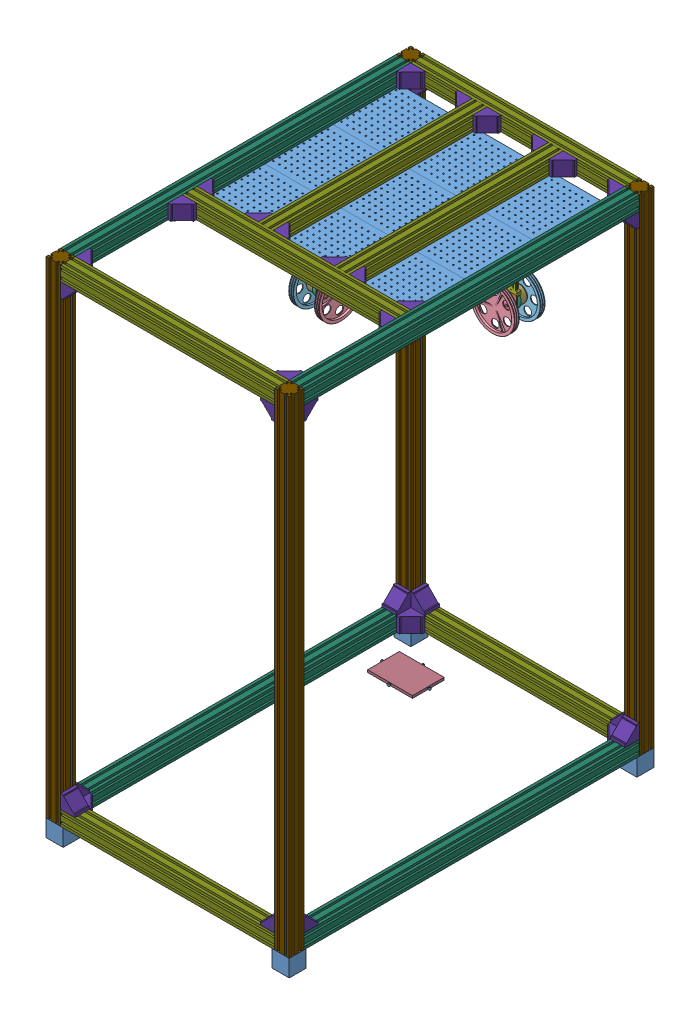
SolidWorks assembly 4轮平台（等比2：3）, configuration 默认. Lengths in mm.
Overall size (1088.36 2070 1500).
157 component instances, 22 part files, 143 mates.
Components (placement in the parent):
- 零件4^4轮平台（等比2：3）-1: 零件4^4轮平台（等比2：3） [默认] at origin (virtual)
- 零件5^4轮平台（等比2：3）-1: 零件5^4轮平台（等比2：3） [默认] at origin (virtual)
- 零件6^4轮平台（等比2：3）-1: 零件6^4轮平台（等比2：3） [默认] at origin (virtual)
- 定位板-1: 定位板 [默认] at (-160 2000 189.3477) x (-1 0 0) z (0 0 1) size (320 10 280)
- 定位板-2: 定位板 [默认] at (-480 2000 189.3477) x (-1 0 0) z (0 0 1) size (320 10 280)
- 定位板-3: 定位板 [默认] at (-800 2000 189.3477) x (-1 0 0) z (0 0 1) size (320 10 280)
- 定位板-4: 定位板 [默认] at (-800 2000 469.3477) x (-1 0 0) z (0 0 1) size (320 10 280)
- 定位板-5: 定位板 [默认] at (-480 2000 469.3477) x (-1 0 0) z (0 0 1) size (320 10 280)
- 定位板-6: 定位板 [默认] at (-160 2000 469.3477) x (-1 0 0) z (0 0 1) size (320 10 280)
- 定位板-7: 定位板 [默认] at (-160 2000 749.3477) x (-1 0 0) z (0 0 1) size (320 10 280)
- 定位板-8: 定位板 [默认] at (-480 2000 749.3477) x (-1 0 0) z (0 0 1) size (320 10 280)
- 定位板-9: 定位板 [默认] at (-800 2000 749.3477) x (-1 0 0) z (0 0 1) size (320 10 280)
- 轮装配体-6: 轮装配体 [默认] at (-1211.0387 1990 471.8477) x (-1 0 0) z (0 0 1) size (248.36 248.36 125.7)
  - 加厚加粗碳纤维竖板-6: 加厚加粗碳纤维竖板 [默认] at (-273.5387 0 0) x (-1 0 0) z (0 -1 0) size (75 5 150)
  - RoboMaster GM6020 直流无刷电机.step-1: RoboMaster GM6020 直流无刷电机.step [默认] at (-311.0387 113 -127.3479) x (0.5 0.866025 0) z (0 0 -1) size (66.7 66.7 45)
  - 卷筒2.2实验-1: 卷筒2.2实验 [默认] at (-311.0387 113 6.7) x (0.534871 -0.844933 0) z (0 0 1) size (180 180 60.8)
  - 卷筒2实验-1: 卷筒2实验 [默认] at (-311.0387 113 -44.8) x (0.534871 -0.844933 0) z (0.844933 0.534871 0) size (180 113.5 180)
  - 加厚加粗电机固定-1: 加厚加粗电机固定 [默认] at (-311.0387 113 -5) x (0.787155 -0.616755 0) z (0.616755 0.787155 0) size (73 20.3 73)
  - L型定位板-1: L型定位板 [默认] at (-361.0387 0 -5) size (100 75 47.4)
  - L型定位板-2: L型定位板 [默认] at (-261.0387 0 0) x (-1 0 0) z (0 0 -1) size (100 75 47.4)
- 轮装配体-7: 轮装配体 [默认] at (-371.0387 1990 471.8477) x (-1 0 0) z (0 0 1) size (248.36 248.36 125.7)
  - 加厚加粗碳纤维竖板-6: 加厚加粗碳纤维竖板 [默认] at (-273.5387 0 0) x (-1 0 0) z (0 -1 0) size (75 5 150)
  - RoboMaster GM6020 直流无刷电机.step-1: RoboMaster GM6020 直流无刷电机.step [默认] at (-311.0387 113 -127.3479) x (0.5 0.866025 0) z (0 0 -1) size (66.7 66.7 45)
  - 卷筒2.2实验-1: 卷筒2.2实验 [默认] at (-311.0387 113 6.7) x (0.534871 -0.844933 0) z (0 0 1) size (180 180 60.8)
  - 卷筒2实验-1: 卷筒2实验 [默认] at (-311.0387 113 -44.8) x (0.534871 -0.844933 0) z (0.844933 0.534871 0) size (180 113.5 180)
  - 加厚加粗电机固定-1: 加厚加粗电机固定 [默认] at (-311.0387 113 -5) x (0.787155 -0.616755 0) z (0.616755 0.787155 0) size (73 20.3 73)
  - L型定位板-1: L型定位板 [默认] at (-361.0387 0 -5) size (100 75 47.4)
  - L型定位板-2: L型定位板 [默认] at (-261.0387 0 0) x (-1 0 0) z (0 0 -1) size (100 75 47.4)
- 轮装配体-8: 轮装配体 [默认] at (-482.5 1990 -171.691) x (0 0 -1) z (-1 0 0) size (248.36 248.36 125.7)
  - 加厚加粗碳纤维竖板-6: 加厚加粗碳纤维竖板 [默认] at (-273.5387 0 0) x (-1 0 0) z (0 -1 0) size (75 5 150)
  - RoboMaster GM6020 直流无刷电机.step-1: RoboMaster GM6020 直流无刷电机.step [默认] at (-311.0387 113 -127.3479) x (0.5 0.866025 0) z (0 0 -1) size (66.7 66.7 45)
  - 卷筒2.2实验-1: 卷筒2.2实验 [默认] at (-311.0387 113 6.7) x (0.534871 -0.844933 0) z (0 0 1) size (180 180 60.8)
  - 卷筒2实验-1: 卷筒2实验 [默认] at (-311.0387 113 -44.8) x (0.534871 -0.844933 0) z (0.844933 0.534871 0) size (180 113.5 180)
  - 加厚加粗电机固定-1: 加厚加粗电机固定 [默认] at (-311.0387 113 -5) x (0.787155 -0.616755 0) z (0.616755 0.787155 0) size (73 20.3 73)
  - L型定位板-1: L型定位板 [默认] at (-361.0387 0 -5) size (100 75 47.4)
  - L型定位板-2: L型定位板 [默认] at (-261.0387 0 0) x (-1 0 0) z (0 0 -1) size (100 75 47.4)
- 轮装配体-9: 轮装配体 [默认] at (-477.5 1990 1110.3863) x (0 0 1) z (1 0 0) size (248.36 248.36 125.7)
  - 加厚加粗碳纤维竖板-6: 加厚加粗碳纤维竖板 [默认] at (-273.5387 0 0) x (-1 0 0) z (0 -1 0) size (75 5 150)
  - RoboMaster GM6020 直流无刷电机.step-1: RoboMaster GM6020 直流无刷电机.step [默认] at (-311.0387 113 -127.3479) x (0.5 0.866025 0) z (0 0 -1) size (66.7 66.7 45)
  - 卷筒2.2实验-1: 卷筒2.2实验 [默认] at (-311.0387 113 6.7) x (0.534871 -0.844933 0) z (0 0 1) size (180 180 60.8)
  - 卷筒2实验-1: 卷筒2实验 [默认] at (-311.0387 113 -44.8) x (0.534871 -0.844933 0) z (0.844933 0.534871 0) size (180 113.5 180)
  - 加厚加粗电机固定-1: 加厚加粗电机固定 [默认] at (-311.0387 113 -5) x (0.787155 -0.616755 0) z (0.616755 0.787155 0) size (73 20.3 73)
  - L型定位板-1: L型定位板 [默认] at (-361.0387 0 -5) size (100 75 47.4)
  - L型定位板-2: L型定位板 [默认] at (-261.0387 0 0) x (-1 0 0) z (0 0 -1) size (100 75 47.4)
- 出绳点链接板-体-1: 出绳点链接板-体 [默认] at (-439.6564 1906.0495 686.8477) x (1 0 0) z (0 0 -1) size (110.44 32.48 49)
  - 出绳点链接板-1: 出绳点链接板 [默认] at (-40.3436 16.0495 0) size (101 23 20)
  - 柱塞螺丝M6-1: 柱塞螺丝M6 [默认] at (-77.8436 22.7895 0) x (-0.70895 0 -0.705258) z (-0.705258 0 0.70895) size (12 14.74 12)
  - 柱塞螺丝M6-2: 柱塞螺丝M6 [默认] at (-2.8436 22.7895 0) x (-0.013162 0 -0.999913) z (-0.999913 0 0.013162) size (12 14.74 12)
  - 零件1^latest1-1: 零件1^latest1 [默认] at (-95.8853 -106.9505 24.5) x (0 0 -1) z (1 0 0) size (28.6 15.58 4.4)
  - 零件1^latest1-2: 零件1^latest1 [默认] at (14.5564 -106.9505 -24.5) x (0 0 1) z (-1 0 0) size (28.6 15.58 4.4)
- 出绳点链接板-体-2: 出绳点链接板-体 [默认] at (-172.5 1906.0495 509.6912) x (0 0 1) z (1 0 0) size (110.44 32.48 49)
  - 出绳点链接板-1: 出绳点链接板 [默认] at (-40.3436 16.0495 0) size (101 23 20)
  - 柱塞螺丝M6-1: 柱塞螺丝M6 [默认] at (-77.8436 22.7895 0) x (-0.70895 0 -0.705258) z (-0.705258 0 0.70895) size (12 14.74 12)
  - 柱塞螺丝M6-2: 柱塞螺丝M6 [默认] at (-2.8436 22.7895 0) x (-0.013162 0 -0.999913) z (-0.999913 0 0.013162) size (12 14.74 12)
  - 零件1^latest1-1: 零件1^latest1 [默认] at (-95.8853 -106.9505 24.5) x (0 0 -1) z (1 0 0) size (28.6 15.58 4.4)
  - 零件1^latest1-2: 零件1^latest1 [默认] at (14.5564 -106.9505 -24.5) x (0 0 1) z (-1 0 0) size (28.6 15.58 4.4)
- 出绳点链接板-体-3: 出绳点链接板-体 [默认] at (-520.3436 1906.0495 251.8477) x (-1 0 0) z (0 0 1) size (110.44 32.48 49)
  - 出绳点链接板-1: 出绳点链接板 [默认] at (-40.3436 16.0495 0) size (101 23 20)
  - 柱塞螺丝M6-1: 柱塞螺丝M6 [默认] at (-77.8436 22.7895 0) x (-0.70895 0 -0.705258) z (-0.705258 0 0.70895) size (12 14.74 12)
  - 柱塞螺丝M6-2: 柱塞螺丝M6 [默认] at (-2.8436 22.7895 0) x (-0.013162 0 -0.999913) z (-0.999913 0 0.013162) size (12 14.74 12)
  - 零件1^latest1-1: 零件1^latest1 [默认] at (-95.8853 -106.9505 24.5) x (0 0 -1) z (1 0 0) size (28.6 15.58 4.4)
  - 零件1^latest1-2: 零件1^latest1 [默认] at (14.5564 -106.9505 -24.5) x (0 0 1) z (-1 0 0) size (28.6 15.58 4.4)
- 出绳点链接板-体-4: 出绳点链接板-体 [默认] at (-787.5 1906.0495 429.0041) x (0 0 -1) z (-1 0 0) size (110.44 32.48 49)
  - 出绳点链接板-1: 出绳点链接板 [默认] at (-40.3436 16.0495 0) size (101 23 20)
  - 柱塞螺丝M6-1: 柱塞螺丝M6 [默认] at (-77.8436 22.7895 0) x (-0.70895 0 -0.705258) z (-0.705258 0 0.70895) size (12 14.74 12)
  - 柱塞螺丝M6-2: 柱塞螺丝M6 [默认] at (-2.8436 22.7895 0) x (-0.013162 0 -0.999913) z (-0.999913 0 0.013162) size (12 14.74 12)
  - 零件1^latest1-1: 零件1^latest1 [默认] at (-95.8853 -106.9505 24.5) x (0 0 -1) z (1 0 0) size (28.6 15.58 4.4)
  - 零件1^latest1-2: 零件1^latest1 [默认] at (14.5564 -106.9505 -24.5) x (0 0 1) z (-1 0 0) size (28.6 15.58 4.4)
- 单头六角柱100-16: 单头六角柱100 [默认] at (-787.5 1890 506.8477) size (18.48 108 16.01)
- 单头六角柱100-17: 单头六角柱100 [默认] at (-787.5 1890 431.8477) size (18.48 108 16.01)
- 单头六角柱100-18: 单头六角柱100 [默认] at (-172.5 1890 506.8477) size (18.48 108 16.01)
- 单头六角柱100-19: 单头六角柱100 [默认] at (-172.5 1890 431.8477) size (18.48 108 16.01)
- 单头六角柱100-20: 单头六角柱100 [默认] at (-442.5 1890 686.8477) size (18.48 108 16.01)
- 单头六角柱100-21: 单头六角柱100 [默认] at (-517.5 1890 686.8477) size (18.48 108 16.01)
- 单头六角柱100-22: 单头六角柱100 [默认] at (-517.5 1890 251.8477) size (18.48 108 16.01)
- 单头六角柱100-23: 单头六角柱100 [默认] at (-442.5 1890 251.8477) size (18.48 108 16.01)
- 定位条-9: 定位条 [默认] at (-317.7 1990 76.8477) x (-1 0 0) z (0 0 1) size (100 9.8 20.25)
- 定位条-10: 定位条 [默认] at (-317.7 1990 301.8477) x (-1 0 0) z (0 0 1) size (100 9.8 20.25)
- 定位条-11: 定位条 [默认] at (-637.7 1990 76.8477) x (-1 0 0) z (0 0 1) size (100 9.8 20.25)
- 定位条-12: 定位条 [默认] at (-637.7 1990 301.8477) x (-1 0 0) z (0 0 1) size (100 9.8 20.25)
- 定位条-13: 定位条 [默认] at (-317.7 1990 861.8477) x (-1 0 0) z (0 0 1) size (100 9.8 20.25)
- 定位条-14: 定位条 [默认] at (-317.7 1990 636.8477) x (-1 0 0) z (0 0 1) size (100 9.8 20.25)
- 定位条-15: 定位条 [默认] at (-317.7 1990 356.8477) x (-1 0 0) z (0 0 1) size (100 9.8 20.25)
- 定位条-16: 定位条 [默认] at (-317.7 1990 581.8477) x (-1 0 0) z (0 0 1) size (100 9.8 20.25)
- 定位条-17: 定位条 [默认] at (-637.7 1990 861.8477) x (-1 0 0) z (0 0 1) size (100 9.8 20.25)
- 定位条-18: 定位条 [默认] at (-637.7 1990 636.8477) x (-1 0 0) z (0 0 1) size (100 9.8 20.25)
- 定位条-19: 定位条 [默认] at (-637.7 1990 356.8477) x (-1 0 0) z (0 0 1) size (100 9.8 20.25)
- 定位条-20: 定位条 [默认] at (-637.7 1990 581.8477) x (-1 0 0) z (0 0 1) size (100 9.8 20.25)
- 定位条-21: 定位条 [默认] at (-247.5 1990 326.6477) x (0 0 -1) z (-1 0 0) size (100 9.8 20.25)
- 定位条-22: 定位条 [默认] at (-72.5 1990 326.6477) x (0 0 -1) z (-1 0 0) size (100 9.8 20.25)
- 定位条-23: 定位条 [默认] at (-247.5 1990 606.6477) x (0 0 -1) z (-1 0 0) size (100 9.8 20.25)
- 定位条-24: 定位条 [默认] at (-72.5 1990 606.6477) x (0 0 -1) z (-1 0 0) size (100 9.8 20.25)
- 定位条-25: 定位条 [默认] at (-712.5 1990 326.6477) x (0 0 -1) z (-1 0 0) size (100 9.8 20.25)
- 定位条-26: 定位条 [默认] at (-887.5 1990 326.6477) x (0 0 -1) z (-1 0 0) size (100 9.8 20.25)
- 定位条-27: 定位条 [默认] at (-712.5 1990 606.6477) x (0 0 -1) z (-1 0 0) size (100 9.8 20.25)
- 定位条-28: 定位条 [默认] at (-887.5 1990 606.6477) x (0 0 -1) z (-1 0 0) size (100 9.8 20.25)
- 铝板（2：3；130.5：184.5）-1: 铝板（2：3；130.5：184.5） [默认] at (-480 334.5585 469.3477) x (0 0 1) z (1 0 0) size (130.5 10 184.5)
- 螺丝配件-1: 螺丝配件 [默认] at (-480 329.5585 539.5977) x (0 -1 0) z (0 0 -1) size (9.5 10 18)
- 螺丝配件-2: 螺丝配件 [默认] at (-480 329.5585 399.0977) x (0 1 0) z (0 0 1) size (9.5 10 18)
- 螺丝配件-3: 螺丝配件 [默认] at (-382.75 329.5585 469.3477) x (0 -1 0) z (-1 0 0) size (9.5 10 18)
- 螺丝配件-4: 螺丝配件 [默认] at (-577.25 329.5585 469.3477) x (0 1 0) z (1 0 0) size (9.5 10 18)
- 框架-4: 框架 [默认] at (-881.2036 2030 721.2518) x (1 0 0) z (0 1 0) size (1000 1500 2070)
  - 框架（水平 大）-1: 框架（水平 大） [默认] at (-98.7964 -668.0959 30) size (60 1380 60)
  - 框架（水平 大）-2: 框架（水平 大） [默认] at (841.2036 -668.0959 30) size (60 1380 60)
  - 框架（水平 小）-1: 框架（水平 小） [默认] at (841.2036 711.9041 30) x (0 1 0) z (0 0 1) size (60 880 60)
  - 框架（水平 小）-2: 框架（水平 小） [默认] at (841.2036 -228.0959 30) x (0 1 0) z (0 0 1) size (60 880 60)
  - 框架（水平 小）-6: 框架（水平 小） [默认] at (841.2036 -728.0959 30) x (0 1 0) z (0 0 1) size (60 880 60)
  - 外角件-1: 外角件 [默认] at (-38.7964 -668.0959 -30) size (58 58 60)
  - 外角件-2: 外角件 [默认] at (841.2036 -668.0959 -30) x (0 1 0) z (0 0 1) size (58 58 60)
  - 外角件-3: 外角件 [默认] at (841.2036 -228.0959 -30) x (-1 0 0) z (0 0 1) size (58 58 60)
  - 外角件-4: 外角件 [默认] at (-38.7964 -228.0959 30) x (1 0 0) z (0 0 -1) size (58 58 60)
  - 外角件-5: 外角件 [默认] at (-38.7964 -168.0959 -30) size (58 58 60)
  - 外角件-6: 外角件 [默认] at (527.8703 -168.0959 -30) x (0 1 0) z (0 0 1) size (58 58 60)
  - 外角件-7: 外角件 [默认] at (-38.7964 711.9041 -30) x (0 -1 0) z (0 0 1) size (58 58 60)
  - 外角件-8: 外角件 [默认] at (527.8703 711.9041 30) x (0 -1 0) z (0 0 -1) size (58 58 60)
  - 外角件-9: 外角件 [默认] at (587.8703 -168.0959 -30) size (58 58 60)
  - 外角件-10: 外角件 [默认] at (841.2036 -168.0959 -30) x (0 1 0) z (0 0 1) size (58 58 60)
  - 外角件-11: 外角件 [默认] at (587.8703 711.9041 -30) x (0 -1 0) z (0 0 1) size (58 58 60)
  - 外角件-12: 外角件 [默认] at (841.2036 711.9041 -30) x (-1 0 0) z (0 0 1) size (58 58 60)
  - 框架（竖直）-1: 框架（竖直） [默认] at (-38.7964 771.9041 30) x (0 -1 0) z (1 0 0) size (60 2000 60)
  - 框架（竖直）-2: 框架（竖直） [默认] at (901.2036 711.9041 30) x (-1 0 0) z (0 -1 0) size (60 2000 60)
  - 框架（竖直）-3: 框架（竖直） [默认] at (-98.7964 -728.0959 -1970) x (1 0 0) z (0 -1 0) size (60 2000 60)
  - 框架（竖直）-4: 框架（竖直） [默认] at (841.2036 -668.0959 30) x (1 0 0) z (0 1 0) size (60 2000 60)
  - 框架（水平 小）-7: 框架（水平 小） [默认] at (841.2036 711.9041 -1970) x (0 0 1) z (0 -1 0) size (60 880 60)
  - 框架（水平 小）-8: 框架（水平 小） [默认] at (-38.7964 -668.0959 -1910) x (0 -1 0) z (0 0 1) size (60 880 60)
  - 框架（水平 大）-3: 框架（水平 大） [默认] at (901.2036 -668.0959 -1910) x (0 0 -1) z (1 0 0) size (60 1380 60)
  - 框架（水平 大）-4: 框架（水平 大） [默认] at (-98.7964 -668.0959 -1910) size (60 1380 60)
  - 外角件-13: 外角件 [默认] at (-38.7964 -668.0959 -1970) size (58 58 60)
  - 外角件-14: 外角件 [默认] at (841.2036 711.9041 -1970) x (-1 0 0) z (0 0 1) size (58 58 60)
  - 外角件-15: 外角件 [默认] at (841.2036 -668.0959 -1970) x (0 1 0) z (0 0 1) size (58 58 60)
  - 外角件-16: 外角件 [默认] at (-38.7964 711.9041 -1910) x (1 0 0) z (0 0 -1) size (58 58 60)
  - 外角件-17: 外角件 [默认] at (-98.7964 711.9041 -30) x (0 -1 0) z (1 0 0) size (58 58 60)
  - 外角件-18: 外角件 [默认] at (841.2036 -668.0959 -30) x (0 0 -1) z (1 0 0) size (58 58 60)
  - 外角件-19: 外角件 [默认] at (-38.7964 711.9041 -1910) x (0 -1 0) z (-1 0 0) size (58 58 60)
  - 外角件-20: 外角件 [默认] at (901.2036 -668.0959 -1910) x (0 0 1) z (-1 0 0) size (58 58 60)
  - 外角件-21: 外角件 [默认] at (841.2036 711.9041 -30) x (0 -1 0) z (1 0 0) size (58 58 60)
  - 外角件-22: 外角件 [默认] at (841.2036 771.9041 -1910) x (0 0 1) z (0 -1 0) size (58 58 60)
  - 外角件-23: 外角件 [默认] at (-98.7964 -668.0959 -30) x (0 0 -1) z (1 0 0) size (58 58 60)
  - 外角件-24: 外角件 [默认] at (-38.7964 -668.0959 -1910) x (0 0 1) z (-1 0 0) size (58 58 60)
  - 外角件-25: 外角件 [默认] at (841.2036 -668.0959 -1910) x (0 0 1) z (0 -1 0) size (58 58 60)
  - 外角件-26: 外角件 [默认] at (-38.7964 -728.0959 -30) x (1 0 0) z (0 1 0) size (58 58 60)
  - 外角件-27: 外角件 [默认] at (841.2036 -728.0959 -30) x (0 0 -1) z (0 1 0) size (58 58 60)
  - 外角件-28: 外角件 [默认] at (-38.7964 711.9041 -30) x (1 0 0) z (0 1 0) size (58 58 60)
  - 外角件-29: 外角件 [默认] at (-38.7964 -668.0959 -1910) x (1 0 0) z (0 -1 0) size (58 58 60)
  - 外角件-30: 外角件 [默认] at (841.2036 711.9041 -1910) x (0 0 1) z (1 0 0) size (58 58 60)
  - 外角件-31: 外角件 [默认] at (-38.7964 711.9041 -1910) x (0 0 1) z (0 1 0) size (58 58 60)
  - 外角件-32: 外角件 [默认] at (841.2036 711.9041 -30) x (0 0 -1) z (0 1 0) size (58 58 60)
  - 框架（水平 小）-9: 框架（水平 小） [默认] at (527.8703 -168.0959 30) size (60 880 60)
  - 框架（水平 小）-10: 框架（水平 小） [默认] at (214.537 -168.0959 30) size (60 880 60)
  - 外角件-33: 外角件 [默认] at (274.537 711.9041 -30) x (0 -1 0) z (0 0 1) size (58 58 60)
  - 外角件-34: 外角件 [默认] at (214.537 711.9041 -30) x (-1 0 0) z (0 0 1) size (58 58 60)
  - 外角件-35: 外角件 [默认] at (274.537 -168.0959 -30) size (58 58 60)
  - 外角件-36: 外角件 [默认] at (214.537 -168.0959 -30) x (0 1 0) z (0 0 1) size (58 58 60)
  - 支脚-1: 支脚 [默认] at (831.2036 -728.0959 -1970) size (70 70 70)
  - 支脚-2: 支脚 [默认] at (-98.7964 -728.0959 -1970) size (70 70 70)
  - 支脚-3: 支脚 [默认] at (-98.7964 701.9041 -1970) size (70 70 70)
  - 支脚-4: 支脚 [默认] at (831.2036 701.9041 -1970) size (70 70 70)
Mates (geometry in assembly coordinates):
- 平行2: parallel aligned: plane of 定位板-1 through (-160 2000 189.3477) normal (0 1 0); plane of 定位板-2 through (-480 2000 189.3477) normal (0 1 0)
- 平行6: parallel aligned: line of 定位板-1 through (-4 1990 329.3477) axis (-1 0 0); line of 定位板-2 through (-324 1990 329.3477) axis (-1 0 0)
- 重合127: coincident anti-aligned: line of 定位板-1 through (-320 2000 325.3477) axis (0 0 -1); line of 定位板-2 through (-320 2000 53.3477) axis (0 0 1)
- 重合128: coincident aligned: line of 定位板-1 through (-316 2000 49.3477) axis (1 0 0); line of 定位板-2 through (-636 2000 49.3477) axis (1 0 0)
- 重合130: coincident aligned: line of 定位板-2 through (-324 2000 329.3477) axis (-1 0 0); line of 定位板-3 through (-644 2000 329.3477) axis (-1 0 0)
- 重合132: coincident anti-aligned: line of 定位板-2 through (-640 2000 325.3477) axis (0 0 -1); line of 定位板-3 through (-640 2000 53.3477) axis (0 0 1)
- 重合193: coincident anti-aligned: plane of 定位板-3 through (-640 1990 329.3477) normal (0 0 1); plane of 定位板-4 through (-640 1990 329.3477) normal (0 0 -1)
- 重合194: coincident aligned: plane of 定位板-3 through (-800 1990 189.3477) normal (0 -1 0); plane of 定位板-4 through (-800 1990 469.3477) normal (0 -1 0)
- 重合195: coincident aligned: plane of 定位板-3 through (-960 1990 329.3477) normal (-1 0 0); plane of 定位板-4 through (-960 1990 609.3477) normal (-1 0 0)
- 重合196: coincident anti-aligned: plane of 定位板-4 through (-640 1990 609.3477) normal (1 0 0); plane of 定位板-5 through (-640 1990 609.3477) normal (-1 0 0)
- 重合197: coincident anti-aligned: plane of 定位板-2 through (-320 1990 329.3477) normal (0 0 1); plane of 定位板-5 through (-320 1990 329.3477) normal (0 0 -1)
- 重合198: coincident aligned: plane of 定位板-2 through (-480 1990 189.3477) normal (0 -1 0); plane of 定位板-5 through (-480 1990 469.3477) normal (0 -1 0)
- 重合199: coincident anti-aligned: plane of 定位板-5 through (-320 1990 609.3477) normal (1 0 0); plane of 定位板-6 through (-320 1990 609.3477) normal (-1 0 0)
- 重合200: coincident aligned: plane of 定位板-5 through (-480 1990 469.3477) normal (0 -1 0); plane of 定位板-6 through (-160 1990 469.3477) normal (0 -1 0)
- 重合201: coincident: line of 定位板-1 through (-4 1990 329.3477) axis (-1 0 0); plane of 定位板-6 through (0 1990 329.3477) normal (0 0 -1)
- 重合214: coincident aligned: line of 定位板-8 through (-324 2000 889.3477) axis (-1 0 0); line of 定位板-9 through (-644 2000 889.3477) axis (-1 0 0)
- 重合215: coincident aligned: line of 定位板-7 through (-4 2000 889.3477) axis (-1 0 0); line of 定位板-8 through (-324 2000 889.3477) axis (-1 0 0)
- 重合216: coincident anti-aligned: plane of 定位板-7 through (-320 1990 889.3477) normal (-1 0 0); plane of 定位板-8 through (-320 1990 889.3477) normal (1 0 0)
- 重合217: coincident anti-aligned: plane of 定位板-8 through (-640 1990 889.3477) normal (-1 0 0); plane of 定位板-9 through (-640 1990 889.3477) normal (1 0 0)
- 重合221: coincident anti-aligned: plane of 定位板-4 through (-800 1990 469.3477) normal (0 -1 0); plane of 轮装配体-6/L型定位板-2 through (-950 1990 471.8477) normal (0 1 0)
- 同心10: concentric anti-aligned: cylinder of 定位板-4 through (-937.5 2000 506.8477) axis (0 -1 0) radius 3; cylinder of 轮装配体-6/L型定位板-2 through (-937.5 1986 506.8477) axis (0 1 0) radius 3
- 同心11: concentric anti-aligned: cylinder of 定位板-4 through (-937.5 2000 431.8477) axis (0 -1 0) radius 3; cylinder of 轮装配体-6/L型定位板-1 through (-937.5 1986 431.8477) axis (0 1 0) radius 3
- 重合222: coincident anti-aligned: plane of 定位板-5 through (-480 1990 469.3477) normal (0 -1 0); plane of 轮装配体-7/L型定位板-2 through (-110 1990 471.8477) normal (0 1 0)
- 重合223: coincident anti-aligned: circle of 定位板-6; cylinder of 轮装配体-7/L型定位板-2 through (-22.5 1986 506.8477) axis (0 1 0) radius 3
- 同心13: concentric anti-aligned: cylinder of 定位板-6 through (-97.5 2000 506.8477) axis (0 -1 0) radius 3; cylinder of 轮装配体-7/L型定位板-2 through (-97.5 1986 506.8477) axis (0 1 0) radius 3
- 重合224: coincident anti-aligned: plane of 定位板-3 through (-800 1990 189.3477) normal (0 -1 0); plane of 轮装配体-8/L型定位板-1 through (-477.5 1990 189.3477) normal (0 1 0)
- 同心23: concentric aligned: cylinder of 出绳点链接板-体-4/柱塞螺丝M6-2 through (-787.5 1898 431.8477) axis (0 -1 0) radius 3; cylinder of 单头六角柱100-17 through (-787.5 1898 431.8477) axis (0 -1 0) radius 3
- 重合235: coincident anti-aligned: plane of 出绳点链接板-体-4/出绳点链接板-1 through (-787.5 1890 469.3477) normal (0 1 0); plane of 单头六角柱100-17 through (-787.5 1890 431.8477) normal (0 -1 0)
- 同心24: concentric aligned: cylinder of 出绳点链接板-体-4/柱塞螺丝M6-1 through (-787.5 1898 506.8477) axis (0 -1 0) radius 3; cylinder of 单头六角柱100-16 through (-787.5 1898 506.8477) axis (0 -1 0) radius 3
- 重合236: coincident anti-aligned: plane of 出绳点链接板-体-4/出绳点链接板-1 through (-787.5 1890 469.3477) normal (0 1 0); plane of 单头六角柱100-16 through (-787.5 1890 506.8477) normal (0 -1 0)
- 同心25: concentric aligned: cylinder of 出绳点链接板-体-2/柱塞螺丝M6-1 through (-172.5 1898 431.8477) axis (0 -1 0) radius 3; cylinder of 单头六角柱100-19 through (-172.5 1898 431.8477) axis (0 -1 0) radius 3
- 重合237: coincident anti-aligned: plane of 出绳点链接板-体-2/出绳点链接板-1 through (-172.5 1890 469.3477) normal (0 1 0); plane of 单头六角柱100-19 through (-172.5 1890 431.8477) normal (0 -1 0)
- 同心26: concentric aligned: cylinder of 出绳点链接板-体-2/柱塞螺丝M6-2 through (-172.5 1898 506.8477) axis (0 -1 0) radius 3; cylinder of 单头六角柱100-18 through (-172.5 1898 506.8477) axis (0 -1 0) radius 3
- 重合238: coincident anti-aligned: plane of 出绳点链接板-体-2/出绳点链接板-1 through (-172.5 1890 469.3477) normal (0 1 0); plane of 单头六角柱100-18 through (-172.5 1890 506.8477) normal (0 -1 0)
- 同心27: concentric aligned: cylinder of 出绳点链接板-体-1/柱塞螺丝M6-1 through (-517.5 1898 686.8477) axis (0 -1 0) radius 3; cylinder of 单头六角柱100-21 through (-517.5 1898 686.8477) axis (0 -1 0) radius 3
- 重合239: coincident anti-aligned: plane of 出绳点链接板-体-1/出绳点链接板-1 through (-480 1890 686.8477) normal (0 1 0); plane of 单头六角柱100-21 through (-517.5 1890 686.8477) normal (0 -1 0)
- 同心28: concentric aligned: cylinder of 出绳点链接板-体-1/柱塞螺丝M6-2 through (-442.5 1898 686.8477) axis (0 -1 0) radius 3; cylinder of 单头六角柱100-20 through (-442.5 1898 686.8477) axis (0 -1 0) radius 3
- 重合240: coincident anti-aligned: plane of 出绳点链接板-体-1/出绳点链接板-1 through (-480 1890 686.8477) normal (0 1 0); plane of 单头六角柱100-20 through (-442.5 1890 686.8477) normal (0 -1 0)
- 同心29: concentric aligned: cylinder of 出绳点链接板-体-3/柱塞螺丝M6-1 through (-442.5 1898 251.8477) axis (0 -1 0) radius 3; cylinder of 单头六角柱100-23 through (-442.5 1898 251.8477) axis (0 -1 0) radius 3
- 重合241: coincident anti-aligned: plane of 出绳点链接板-体-3/出绳点链接板-1 through (-480 1890 251.8477) normal (0 1 0); plane of 单头六角柱100-23 through (-442.5 1890 251.8477) normal (0 -1 0)
- 同心30: concentric aligned: cylinder of 出绳点链接板-体-3/柱塞螺丝M6-2 through (-517.5 1898 251.8477) axis (0 -1 0) radius 3; cylinder of 单头六角柱100-22 through (-517.5 1898 251.8477) axis (0 -1 0) radius 3
- 重合242: coincident anti-aligned: plane of 出绳点链接板-体-3/出绳点链接板-1 through (-480 1890 251.8477) normal (0 1 0); plane of 单头六角柱100-22 through (-517.5 1890 251.8477) normal (0 -1 0)
- 同心35: concentric aligned: cylinder of 定位板-4 through (-787.5 2000 431.8477) axis (0 -1 0) radius 3; cylinder of 单头六角柱100-17 through (-787.5 1998 431.8477) axis (0 -1 0) radius 3
- 同心36: concentric aligned: cylinder of 定位板-4 through (-787.5 2000 506.8477) axis (0 -1 0) radius 3; cylinder of 单头六角柱100-16 through (-787.5 1998 506.8477) axis (0 -1 0) radius 3
- 重合246: coincident anti-aligned: plane of 定位板-4 through (-800 1990 469.3477) normal (0 -1 0); plane of 单头六角柱100-16 through (-787.5 1990 506.8477) normal (0 1 0)
- 同心37: concentric aligned: cylinder of 定位板-6 through (-172.5 2000 431.8477) axis (0 -1 0) radius 3; cylinder of 单头六角柱100-19 through (-172.5 1998 431.8477) axis (0 -1 0) radius 3
- 同心38: concentric aligned: cylinder of 定位板-6 through (-172.5 2000 506.8477) axis (0 -1 0) radius 3; cylinder of 单头六角柱100-18 through (-172.5 1998 506.8477) axis (0 -1 0) radius 3
- 重合247: coincident: plane of 定位板-6 through (-160 1990 469.3477) normal (0 -1 0); line of 单头六角柱100-18 through (-177.1107 1990 514.8523) axis (0.999999 0 -0.001013)
- 重合255: coincident aligned: plane of 定位板-8 through (-480 1990 749.3477) normal (0 -1 0); plane of 定位板-9 through (-800 1990 749.3477) normal (0 -1 0)
- 同心43: concentric aligned: cylinder of 定位板-2 through (-517.5 2000 251.8477) axis (0 -1 0) radius 3; cylinder of 单头六角柱100-22 through (-517.5 1998 251.8477) axis (0 -1 0) radius 3
- 同心44: concentric aligned: cylinder of 定位板-2 through (-442.5 2000 251.8477) axis (0 -1 0) radius 3; cylinder of 单头六角柱100-23 through (-442.5 1998 251.8477) axis (0 -1 0) radius 3
- 重合267: coincident: plane of 定位板-6 through (-160 1990 469.3477) normal (0 -1 0); line of 单头六角柱100-22 through (-512.8731 1990 259.843) axis (0.499122 0 -0.866532)
- 重合270: coincident aligned: plane of 定位板-7 through (-160 2000 749.3477) normal (0 1 0); plane of 定位板-8 through (-480 2000 749.3477) normal (0 1 0)
- 重合271: coincident aligned: plane of 定位板-6 through (-160 2000 469.3477) normal (0 1 0); plane of 定位板-7 through (-160 2000 749.3477) normal (0 1 0)
- 重合272: coincident anti-aligned: plane of 定位板-6 through (0 1990 609.3477) normal (0 0 1); plane of 定位板-7 through (0 1990 609.3477) normal (0 0 -1)
- 重合273: coincident aligned: plane of 定位板-6 through (0 1990 609.3477) normal (1 0 0); plane of 定位板-7 through (0 1990 889.3477) normal (1 0 0)
- 同心47: concentric aligned: cylinder of 定位板-8 through (-517.5 2000 686.8477) axis (0 -1 0) radius 3; cylinder of 单头六角柱100-21 through (-517.5 1998 686.8477) axis (0 -1 0) radius 3
- 同心48: concentric aligned: cylinder of 定位板-8 through (-442.5 2000 686.8477) axis (0 -1 0) radius 3; cylinder of 单头六角柱100-20 through (-442.5 1998 686.8477) axis (0 -1 0) radius 3
- 重合275: coincident anti-aligned: plane of 定位板-8 through (-480 1990 749.3477) normal (0 -1 0); plane of 单头六角柱100-20 through (-442.5 1990 686.8477) normal (0 1 0)
- 重合279: coincident anti-aligned: plane of 定位板-8 through (-480 1990 749.3477) normal (0 -1 0); plane of 轮装配体-9/L型定位板-2 through (-477.5 1990 849.3477) normal (0 1 0)
- 同心50: concentric anti-aligned: cylinder of 定位板-8 through (-492.5 2000 761.8477) axis (0 -1 0) radius 3; cylinder of 轮装配体-9/L型定位板-1 through (-492.5 1986 761.8477) axis (0 1 0) radius 3
- 同心51: concentric anti-aligned: cylinder of 定位板-8 through (-467.5 2000 761.8477) axis (0 -1 0) radius 3; cylinder of 轮装配体-9/L型定位板-2 through (-467.5 1986 761.8477) axis (0 1 0) radius 3
- 同心52: concentric anti-aligned: cylinder of 定位板-2 through (-467.5 2000 176.8477) axis (0 -1 0) radius 3; cylinder of 轮装配体-8/L型定位板-1 through (-467.5 1986 176.8477) axis (0 1 0) radius 3
- 同心53: concentric anti-aligned: cylinder of 定位板-2 through (-492.5 2000 176.8477) axis (0 -1 0) radius 3; cylinder of 轮装配体-8/L型定位板-2 through (-492.5 1986 176.8477) axis (0 1 0) radius 3
- 重合280: coincident anti-aligned: plane of 定位板-1 through (-160 1990 189.3477) normal (0 -1 0); plane of 定位条-9 through (-317.7 1990 76.8477) normal (0 1 0)
- 重合281: coincident anti-aligned: plane of 定位板-1 through (-160 1990 189.3477) normal (0 -1 0); plane of 定位条-10 through (-317.7 1990 301.8477) normal (0 1 0)
- 槽口1: slot anti-aligned: cylinder of 定位条-9 through (-354.95 1987 76.8477) axis (0 1 0) radius 3.215; cylinder of 定位板-2 through (-342.5 2000 76.8477) axis (0 -1 0) radius 3; cylinder of 定位条-9 through (-330.05 1987 76.8477) axis (0 1 0) radius 3.215
- 槽口2: slot anti-aligned: cylinder of 定位条-9 through (-305.35 1987 76.8477) axis (0 1 0) radius 3.215; cylinder of 定位板-1 through (-297.5 2000 76.8477) axis (0 -1 0) radius 3; cylinder of 定位条-9 through (-280.45 1987 76.8477) axis (0 1 0) radius 3.215
- 槽口3: slot anti-aligned: cylinder of 定位条-10 through (-354.95 1987 301.8477) axis (0 1 0) radius 3.215; cylinder of 定位板-2 through (-342.5 2000 301.8477) axis (0 -1 0) radius 3; cylinder of 定位条-10 through (-330.05 1987 301.8477) axis (0 1 0) radius 3.215
- 槽口4: slot anti-aligned: cylinder of 定位条-10 through (-305.35 1987 301.8477) axis (0 1 0) radius 3.215; cylinder of 定位板-1 through (-297.5 2000 301.8477) axis (0 -1 0) radius 3; cylinder of 定位条-10 through (-280.45 1987 301.8477) axis (0 1 0) radius 3.215
- 重合282: coincident anti-aligned: plane of 定位板-1 through (-160 1990 189.3477) normal (0 -1 0); plane of 定位条-21 through (-247.5 1990 326.6477) normal (0 1 0)
- 重合283: coincident anti-aligned: plane of 定位板-1 through (-160 1990 189.3477) normal (0 -1 0); plane of 定位条-22 through (-72.5 1990 326.6477) normal (0 1 0)
- 重合284: coincident anti-aligned: plane of 定位板-7 through (-160 1990 749.3477) normal (0 -1 0); plane of 定位条-23 through (-247.5 1990 606.6477) normal (0 1 0)
- 重合285: coincident anti-aligned: plane of 定位板-7 through (-160 1990 749.3477) normal (0 -1 0); plane of 定位条-24 through (-72.5 1990 606.6477) normal (0 1 0)
- 重合286: coincident anti-aligned: plane of 定位板-7 through (-160 1990 749.3477) normal (0 -1 0); plane of 定位条-13 through (-317.7 1990 861.8477) normal (0 1 0)
- 重合287: coincident anti-aligned: plane of 定位板-7 through (-160 1990 749.3477) normal (0 -1 0); plane of 定位条-14 through (-317.7 1990 636.8477) normal (0 1 0)
- 重合288: coincident anti-aligned: plane of 定位板-7 through (-160 1990 749.3477) normal (0 -1 0); plane of 定位条-15 through (-317.7 1990 356.8477) normal (0 1 0)
- 重合289: coincident anti-aligned: plane of 定位板-8 through (-480 1990 749.3477) normal (0 -1 0); plane of 定位条-16 through (-317.7 1990 581.8477) normal (0 1 0)
- 重合290: coincident anti-aligned: plane of 定位板-3 through (-800 1990 189.3477) normal (0 -1 0); plane of 定位条-17 through (-637.7 1990 861.8477) normal (0 1 0)
- 重合291: coincident anti-aligned: plane of 定位板-3 through (-800 1990 189.3477) normal (0 -1 0); plane of 定位条-18 through (-637.7 1990 636.8477) normal (0 1 0)
- 重合292: coincident anti-aligned: plane of 定位板-3 through (-800 1990 189.3477) normal (0 -1 0); plane of 定位条-19 through (-637.7 1990 356.8477) normal (0 1 0)
- 重合293: coincident anti-aligned: plane of 定位板-3 through (-800 1990 189.3477) normal (0 -1 0); plane of 定位条-20 through (-637.7 1990 581.8477) normal (0 1 0)
- 重合294: coincident anti-aligned: plane of 定位板-3 through (-800 1990 189.3477) normal (0 -1 0); plane of 定位条-25 through (-712.5 1990 326.6477) normal (0 1 0)
- 重合295: coincident anti-aligned: plane of 定位板-3 through (-800 1990 189.3477) normal (0 -1 0); plane of 定位条-26 through (-887.5 1990 326.6477) normal (0 1 0)
- 重合296: coincident anti-aligned: plane of 定位板-9 through (-800 1990 749.3477) normal (0 -1 0); plane of 定位条-27 through (-712.5 1990 606.6477) normal (0 1 0)
- 重合297: coincident anti-aligned: plane of 定位板-9 through (-800 1990 749.3477) normal (0 -1 0); plane of 定位条-28 through (-887.5 1990 606.6477) normal (0 1 0)
- 重合298: coincident anti-aligned: plane of 定位板-2 through (-480 1990 189.3477) normal (0 -1 0); plane of 定位条-12 through (-637.7 1990 301.8477) normal (0 1 0)
- 重合299: coincident anti-aligned: plane of 定位板-2 through (-480 1990 189.3477) normal (0 -1 0); plane of 定位条-11 through (-637.7 1990 76.8477) normal (0 1 0)
- 槽口5: slot anti-aligned: cylinder of 定位条-11 through (-674.95 1987 76.8477) axis (0 1 0) radius 3.215; cylinder of 定位板-3 through (-662.5 2000 76.8477) axis (0 -1 0) radius 3; cylinder of 定位条-11 through (-650.05 1987 76.8477) axis (0 1 0) radius 3.215
- 槽口7: slot anti-aligned: cylinder of 定位条-21 through (-247.5 1987 289.3977) axis (0 1 0) radius 3.215; cylinder of 定位板-1 through (-247.5 2000 301.8477) axis (0 -1 0) radius 3; cylinder of 定位条-21 through (-247.5 1987 314.2977) axis (0 1 0) radius 3.215
- 槽口8: slot anti-aligned: cylinder of 定位条-22 through (-72.5 1987 289.3977) axis (0 1 0) radius 3.215; cylinder of 定位板-1 through (-72.5 2000 301.8477) axis (0 -1 0) radius 3; cylinder of 定位条-22 through (-72.5 1987 314.2977) axis (0 1 0) radius 3.215
- 槽口9: slot anti-aligned: cylinder of 定位条-25 through (-712.5 1987 289.3977) axis (0 1 0) radius 3.215; cylinder of 定位板-3 through (-712.5 2000 301.8477) axis (0 -1 0) radius 3; cylinder of 定位条-25 through (-712.5 1987 314.2977) axis (0 1 0) radius 3.215
- 槽口10: slot anti-aligned: cylinder of 定位条-26 through (-887.5 1987 289.3977) axis (0 1 0) radius 3.215; cylinder of 定位板-3 through (-887.5 2000 301.8477) axis (0 -1 0) radius 3; cylinder of 定位条-26 through (-887.5 1987 314.2977) axis (0 1 0) radius 3.215
- 槽口11: slot anti-aligned: cylinder of 定位条-23 through (-247.5 1987 569.3977) axis (0 1 0) radius 3.215; cylinder of 定位板-6 through (-247.5 2000 581.8477) axis (0 -1 0) radius 3; cylinder of 定位条-23 through (-247.5 1987 594.2977) axis (0 1 0) radius 3.215
- 槽口12: slot anti-aligned: cylinder of 定位条-24 through (-72.5 1987 569.3977) axis (0 1 0) radius 3.215; cylinder of 定位板-6 through (-72.5 2000 581.8477) axis (0 -1 0) radius 3; cylinder of 定位条-24 through (-72.5 1987 594.2977) axis (0 1 0) radius 3.215
- 槽口13: slot anti-aligned: cylinder of 定位条-13 through (-354.95 1987 861.8477) axis (0 1 0) radius 3.215; cylinder of 定位板-8 through (-342.5 2000 861.8477) axis (0 -1 0) radius 3; cylinder of 定位条-13 through (-330.05 1987 861.8477) axis (0 1 0) radius 3.215
- 槽口14: slot anti-aligned: cylinder of 定位条-14 through (-354.95 1987 636.8477) axis (0 1 0) radius 3.215; cylinder of 定位板-8 through (-342.5 2000 636.8477) axis (0 -1 0) radius 3; cylinder of 定位条-14 through (-330.05 1987 636.8477) axis (0 1 0) radius 3.215
- 槽口15: slot anti-aligned: cylinder of 定位条-15 through (-354.95 1987 356.8477) axis (0 1 0) radius 3.215; cylinder of 定位板-5 through (-342.5 2000 356.8477) axis (0 -1 0) radius 3; cylinder of 定位条-15 through (-330.05 1987 356.8477) axis (0 1 0) radius 3.215
- 槽口16: slot anti-aligned: cylinder of 定位条-16 through (-354.95 1987 581.8477) axis (0 1 0) radius 3.215; cylinder of 定位板-5 through (-342.5 2000 581.8477) axis (0 -1 0) radius 3; cylinder of 定位条-16 through (-330.05 1987 581.8477) axis (0 1 0) radius 3.215
- 槽口17: slot anti-aligned: cylinder of 定位条-17 through (-674.95 1987 861.8477) axis (0 1 0) radius 3.215; cylinder of 定位板-9 through (-662.5 2000 861.8477) axis (0 -1 0) radius 3; cylinder of 定位条-17 through (-650.05 1987 861.8477) axis (0 1 0) radius 3.215
- 槽口19: slot anti-aligned: cylinder of 定位条-19 through (-674.95 1987 356.8477) axis (0 1 0) radius 3.215; cylinder of 定位板-4 through (-662.5 2000 356.8477) axis (0 -1 0) radius 3; cylinder of 定位条-19 through (-650.05 1987 356.8477) axis (0 1 0) radius 3.215
- 槽口20: slot anti-aligned: cylinder of 定位条-20 through (-674.95 1987 581.8477) axis (0 1 0) radius 3.215; cylinder of 定位板-4 through (-662.5 2000 581.8477) axis (0 -1 0) radius 3; cylinder of 定位条-20 through (-650.05 1987 581.8477) axis (0 1 0) radius 3.215
- 槽口21: slot anti-aligned: cylinder of 定位条-27 through (-712.5 1987 569.3977) axis (0 1 0) radius 3.215; cylinder of 定位板-4 through (-712.5 2000 581.8477) axis (0 -1 0) radius 3; cylinder of 定位条-27 through (-712.5 1987 594.2977) axis (0 1 0) radius 3.215
- 槽口22: slot anti-aligned: cylinder of 定位条-28 through (-887.5 1987 569.3977) axis (0 1 0) radius 3.215; cylinder of 定位板-4 through (-887.5 2000 581.8477) axis (0 -1 0) radius 3; cylinder of 定位条-28 through (-887.5 1987 594.2977) axis (0 1 0) radius 3.215
- 槽口23: slot anti-aligned: cylinder of 定位条-11 through (-625.35 1987 76.8477) axis (0 1 0) radius 3.215; cylinder of 定位板-2 through (-617.5 2000 76.8477) axis (0 -1 0) radius 3; cylinder of 定位条-11 through (-600.45 1987 76.8477) axis (0 1 0) radius 3.215
- 槽口25: slot anti-aligned: plane of 定位条-25 through (-715.715 1987 326.6477) normal (1 0 0); cylinder of 定位板-4 through (-712.5 2000 356.8477) axis (0 -1 0) radius 3; cylinder of 定位条-25 through (-712.5 1987 363.8977) axis (0 1 0) radius 3.215
- 槽口26: slot anti-aligned: cylinder of 定位条-19 through (-625.35 1987 356.8477) axis (0 1 0) radius 3.215; cylinder of 定位板-5 through (-617.5 2000 356.8477) axis (0 -1 0) radius 3; cylinder of 定位条-19 through (-600.45 1987 356.8477) axis (0 1 0) radius 3.215
- 槽口27: slot anti-aligned: cylinder of 定位条-26 through (-887.5 1987 338.9977) axis (0 1 0) radius 3.215; cylinder of 定位板-4 through (-887.5 2000 356.8477) axis (0 -1 0) radius 3; cylinder of 定位条-26 through (-887.5 1987 363.8977) axis (0 1 0) radius 3.215
- 槽口28: slot anti-aligned: cylinder of 定位条-22 through (-72.5 1987 338.9977) axis (0 1 0) radius 3.215; cylinder of 定位板-6 through (-72.5 2000 356.8477) axis (0 -1 0) radius 3; cylinder of 定位条-22 through (-72.5 1987 363.8977) axis (0 1 0) radius 3.215
- 槽口29: slot anti-aligned: cylinder of 定位条-15 through (-305.35 1987 356.8477) axis (0 1 0) radius 3.215; cylinder of 定位板-6 through (-297.5 2000 356.8477) axis (0 -1 0) radius 3; cylinder of 定位条-15 through (-280.45 1987 356.8477) axis (0 1 0) radius 3.215
- 槽口30: slot anti-aligned: cylinder of 定位条-24 through (-72.5 1987 618.9977) axis (0 1 0) radius 3.215; cylinder of 定位板-7 through (-72.5 2000 636.8477) axis (0 -1 0) radius 3; cylinder of 定位条-24 through (-72.5 1987 643.8977) axis (0 1 0) radius 3.215
- 槽口31: slot anti-aligned: cylinder of 定位条-23 through (-247.5 1987 618.9977) axis (0 1 0) radius 3.215; cylinder of 定位板-7 through (-247.5 2000 636.8477) axis (0 -1 0) radius 3; cylinder of 定位条-23 through (-247.5 1987 643.8977) axis (0 1 0) radius 3.215
- 槽口32: slot anti-aligned: cylinder of 定位条-16 through (-305.35 1987 581.8477) axis (0 1 0) radius 3.215; cylinder of 定位板-6 through (-297.5 2000 581.8477) axis (0 -1 0) radius 3; cylinder of 定位条-16 through (-280.45 1987 581.8477) axis (0 1 0) radius 3.215
- 槽口33: slot anti-aligned: cylinder of 定位条-14 through (-305.35 1987 636.8477) axis (0 1 0) radius 3.215; cylinder of 定位板-7 through (-297.5 2000 636.8477) axis (0 -1 0) radius 3; cylinder of 定位条-14 through (-280.45 1987 636.8477) axis (0 1 0) radius 3.215
- 槽口34: slot anti-aligned: cylinder of 定位条-13 through (-305.35 1987 861.8477) axis (0 1 0) radius 3.215; cylinder of 定位板-7 through (-297.5 2000 861.8477) axis (0 -1 0) radius 3; cylinder of 定位条-13 through (-280.45 1987 861.8477) axis (0 1 0) radius 3.215
- 槽口35: slot anti-aligned: cylinder of 定位条-17 through (-625.35 1987 861.8477) axis (0 1 0) radius 3.215; cylinder of 定位板-8 through (-617.5 2000 861.8477) axis (0 -1 0) radius 3; cylinder of 定位条-17 through (-600.45 1987 861.8477) axis (0 1 0) radius 3.215
- 槽口36: slot anti-aligned: cylinder of 定位条-20 through (-625.35 1987 581.8477) axis (0 1 0) radius 3.215; cylinder of 定位板-5 through (-617.5 2000 581.8477) axis (0 -1 0) radius 3; cylinder of 定位条-20 through (-600.45 1987 581.8477) axis (0 1 0) radius 3.215
- 槽口37: slot anti-aligned: cylinder of 定位条-18 through (-674.95 1987 636.8477) axis (0 1 0) radius 3.215; cylinder of 定位板-9 through (-662.5 2000 636.8477) axis (0 -1 0) radius 3; cylinder of 定位条-18 through (-650.05 1987 636.8477) axis (0 1 0) radius 3.215
- 槽口38: slot anti-aligned: cylinder of 定位条-18 through (-625.35 1987 636.8477) axis (0 1 0) radius 3.215; cylinder of 定位板-8 through (-617.5 2000 636.8477) axis (0 -1 0) radius 3; cylinder of 定位条-18 through (-600.45 1987 636.8477) axis (0 1 0) radius 3.215
- 槽口39: slot anti-aligned: cylinder of 定位条-27 through (-712.5 1987 618.9977) axis (0 1 0) radius 3.215; cylinder of 定位板-9 through (-712.5 2000 636.8477) axis (0 -1 0) radius 3; cylinder of 定位条-27 through (-712.5 1987 643.8977) axis (0 1 0) radius 3.215
- 槽口40: slot anti-aligned: cylinder of 定位条-28 through (-887.5 1987 618.9977) axis (0 1 0) radius 3.215; cylinder of 定位板-9 through (-887.5 2000 636.8477) axis (0 -1 0) radius 3; cylinder of 定位条-28 through (-887.5 1987 643.8977) axis (0 1 0) radius 3.215
- 槽口41: slot anti-aligned: plane of 定位条-12 through (-637.7 1987 298.6327) normal (0 0 1); cylinder of 定位板-3 through (-662.5 2000 301.8477) axis (0 -1 0) radius 3; cylinder of 定位条-12 through (-674.95 1987 301.8477) axis (0 1 0) radius 3.215
- 槽口42: slot anti-aligned: plane of 定位条-12 through (-637.7 1987 298.6327) normal (0 0 1); cylinder of 定位板-2 through (-617.5 2000 301.8477) axis (0 -1 0) radius 3; cylinder of 定位条-12 through (-625.35 1987 301.8477) axis (0 1 0) radius 3.215
- 同心56: concentric aligned: cylinder of 铝板（2：3；130.5：184.5）-1 through (-480 329.5585 414.0977) axis (0 0 -1) radius 3.5; cylinder of 螺丝配件-2 through (-480 329.5585 412.0977) axis (0 0 -1) radius 3.5
- 重合302: coincident anti-aligned: plane of 铝板（2：3；130.5：184.5）-1 through (-387.75 324.5585 404.0977) normal (0 0 -1); plane of 螺丝配件-2 through (-480 329.5585 404.0977) normal (0 0 1)
- 平行53: parallel anti-aligned: line of 铝板（2：3；130.5：184.5）-1 through (-572.25 324.5585 404.0977) axis (1 0 0); line of 螺丝配件-2 through (-479.5 329.5585 399.5977) axis (-1 0 0)
- 同心58: concentric aligned: cylinder of 铝板（2：3；130.5：184.5）-1 through (-397.75 329.5585 469.3477) axis (1 0 0) radius 3.5; cylinder of 螺丝配件-3 through (-395.75 329.5585 469.3477) axis (1 0 0) radius 3.5
- 重合308: coincident anti-aligned: plane of 铝板（2：3；130.5：184.5）-1 through (-387.75 324.5585 404.0977) normal (1 0 0); plane of 螺丝配件-3 through (-387.75 329.5585 469.3477) normal (-1 0 0)
- 同心59: concentric aligned: cylinder of 铝板（2：3；130.5：184.5）-1 through (-480 329.5585 524.5977) axis (0 0 1) radius 3.5; cylinder of 螺丝配件-1 through (-480 329.5585 526.5977) axis (0 0 1) radius 3.5
- 重合309: coincident anti-aligned: plane of 铝板（2：3；130.5：184.5）-1 through (-387.75 324.5585 534.5977) normal (0 0 1); plane of 螺丝配件-1 through (-480 329.5585 534.5977) normal (0 0 -1)
- 同心60: concentric aligned: cylinder of 铝板（2：3；130.5：184.5）-1 through (-562.25 329.5585 469.3477) axis (-1 0 0) radius 3.5; cylinder of 螺丝配件-4 through (-564.25 329.5585 469.3477) axis (-1 0 0) radius 3.5
- 重合310: coincident anti-aligned: plane of 铝板（2：3；130.5：184.5）-1 through (-572.25 324.5585 404.0977) normal (-1 0 0); plane of 螺丝配件-4 through (-572.25 329.5585 469.3477) normal (1 0 0)
- 平行54: parallel aligned: line of 铝板（2：3；130.5：184.5）-1 through (-387.75 324.5585 534.5977) axis (-1 0 0); line of 螺丝配件-1 through (-479.5 329.5585 539.0977) axis (-1 0 0)
- 平行55: parallel anti-aligned: line of 铝板（2：3；130.5：184.5）-1 through (-572.25 324.5585 534.5977) axis (0 0 -1); line of 螺丝配件-4 through (-576.75 329.5585 468.8477) axis (0 0 1)
- 平行57: parallel anti-aligned: line of 铝板（2：3；130.5：184.5）-1 through (-572.25 324.5585 404.0977) axis (1 0 0); line of 螺丝配件-2 through (-479.5 329.5585 399.5977) axis (-1 0 0)
- 距离10: distance = 387.75 mm aligned: plane of 铝板（2：3；130.5：184.5）-1 through (-572.25 324.5585 404.0977) normal (-1 0 0); plane of 定位板-4 through (-960 1990 609.3477) normal (-1 0 0)
- 距离12: distance = 354.75 mm aligned: plane of 铝板（2：3；130.5：184.5）-1 through (-387.75 324.5585 534.5977) normal (0 0 1); plane of 定位板-8 through (-320 1990 889.3477) normal (0 0 1)
- 平行61: parallel aligned: line of 铝板（2：3；130.5：184.5）-1 through (-387.75 334.5585 404.0977) axis (0 0 1); line of 螺丝配件-3 through (-383.25 329.5585 468.8477) axis (0 0 1)
- 重合319: coincident aligned: plane of 定位板-6 through (0 1990 609.3477) normal (1 0 0)
- 距离13: distance = 2000 mm: plane of assembly through (0 0 0) normal (0 1 0); plane of assembly; plane of 定位板-8 through (-480 2000 749.3477) normal (0 1 0)
- 重合327: coincident anti-aligned: plane of 定位板-5 through (-480 2000 469.3477) normal (0 1 0); plane of 框架-4/框架（水平 小）-9 through (-353.3333 2000 9.3477) normal (0 -1 0)
- 距离16: distance = 20 mm aligned: plane of 框架-4/框架（水平 大）-1 through (-980 2060 9.3477) normal (-1 0 0); plane of 定位板-4 through (-960 1990 609.3477) normal (-1 0 0)
- 重合329: coincident anti-aligned: plane of 定位板-8 through (-320 1990 889.3477) normal (0 0 1); plane of 框架-4/框架（水平 小）-2 through (-920 2060 889.3477) normal (0 0 -1)
